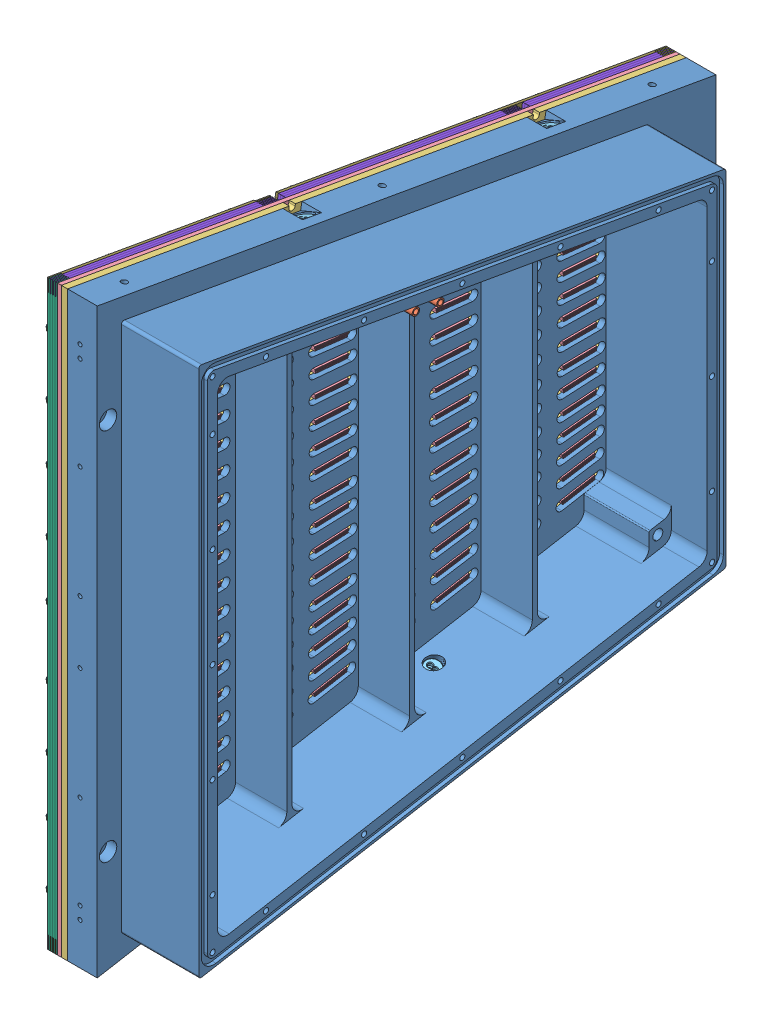
SolidWorks assembly KP_ALICE_TPC_UPGR_IROC_906100_A_0__IROC, configuration Default. Lengths in mm.
Overall size (107.25 467.04 496.5).
180 component instances, 16 part files, 0 mates.
Components (placement in the parent):
- KP_ALICE_TPC_UPGR_IROC_006100_P_0__IROC_alubody-1: KP_ALICE_TPC_UPGR_IROC_006100_P_0__IROC_alubody [Default] at origin size (85.8 467.04 496.5)
- KP_ALICE_TPC_UPGR_IROC_006200_P_0__IROC_cooling_pipe-1: KP_ALICE_TPC_UPGR_IROC_006200_P_0__IROC_cooling_pipe [Default] at origin size (87.18 411.15 421)
- KP_ALICE_TPC_UPGR_IROC_006110_P_0__IROC_strongback-1: KP_ALICE_TPC_UPGR_IROC_006110_P_0__IROC_strongback [Default] at origin size (5 467.04 496.5)
- KP_ALICE_TPC_UPGR_IROC_PADPL_006010_P_0__IROC_padplane-1: KP_ALICE_TPC_UPGR_IROC_PADPL_006010_P_0__IROC_padplane [Default] at (-5 0 0) size (12.25 467.04 496.5)
- KP_ALICE_TPC_UPGR_IROC_006105_P_0__Plug_Feedthrough-1: KP_ALICE_TPC_UPGR_IROC_006105_P_0__Plug_Feedthrough [Default] at (18.3176 -157.7833 228.3194) x (-0.93358 0.352924 0.06223) z (0 -0.173648 0.984808) size (14.4 25.16 13.6)
- KP_ALICE_TPC_UPGR_IROC_006105_P_0__Plug_Feedthrough-2: KP_ALICE_TPC_UPGR_IROC_006105_P_0__Plug_Feedthrough [Default] at (18.3176 -193.8152 432.667) x (-0.93358 0.352924 0.06223) z (0 -0.173648 0.984808) size (14.4 25.16 13.6)
- KP_ALICE_TPC_UPGR_IROC_006105_P_0__Plug_Feedthrough-3: KP_ALICE_TPC_UPGR_IROC_006105_P_0__Plug_Feedthrough [Default] at (18.3176 140.6789 131.3158) x (-0.93358 -0.352924 0.06223) z (0 -0.173648 -0.984808) size (14.4 25.16 13.6)
- KP_ALICE_TPC_UPGR_IROC_006105_P_0__Plug_Feedthrough-4: KP_ALICE_TPC_UPGR_IROC_006105_P_0__Plug_Feedthrough [Default] at (18.3176 175.2349 327.2925) x (-0.93358 -0.352924 0.06223) z (0 -0.173648 -0.984808) size (14.4 25.16 13.6)
- KP_ALICE_TPC_UPGR_GEM_GIF_906300_A_0__IROC-GEM-frame-1: KP_ALICE_TPC_UPGR_GEM_GIF_906300_A_0__IROC-GEM-frame [Default] at (-2.2 0 0) size (2 467.04 496.5)
  - KP_ALICE_TPC_UPGR_GEM_GIF_006310_P_0__IROC-GEM-frame-top-1: KP_ALICE_TPC_UPGR_GEM_GIF_006310_P_0__IROC-GEM-frame-top [Default] at (-6 0 0) size (2 467.04 10)
  - KP_ALICE_TPC_UPGR_GEM_GIF_006320_P_0__IROC-GEM-frame-bottom-1: KP_ALICE_TPC_UPGR_GEM_GIF_006320_P_0__IROC-GEM-frame-bottom [Default] at (-6 0 0) size (2 295.48 10)
  - KP_ALICE_TPC_UPGR_GEM_GIF_006330_P_0__IROC-GEM-frame-left-1: KP_ALICE_TPC_UPGR_GEM_GIF_006330_P_0__IROC-GEM-frame-left [Default] at (-6 0 0) size (2 97.7 496.5)
  - KP_ALICE_TPC_UPGR_GEM_GIF_006340_P_0__IROC-GEM-frame-right-1: KP_ALICE_TPC_UPGR_GEM_GIF_006340_P_0__IROC-GEM-frame-right [Default] at (-6 0 0) size (2 97.7 496.5)
  - KP_ALICE_TPC_UPGR_GEM_GIF_006351_P_0__IROC-GEM-frame-distance-strip_V-1: KP_ALICE_TPC_UPGR_GEM_GIF_006351_P_0__IROC-GEM-frame-distance-strip_V [Default] at (-6 0 0) size (2 1.5 481)
  - KP_ALICE_TPC_UPGR_GEM_GIF_006361_P_0__IROC-GEM-frame-distance-strip_H-1: KP_ALICE_TPC_UPGR_GEM_GIF_006361_P_0__IROC-GEM-frame-distance-strip_H [Default] at (-6 0 0) size (2 364.51 1.5)
- KP_ALICE_TPC_UPGR_GEM_GIF_906300_A_0__IROC-GEM-frame-2: KP_ALICE_TPC_UPGR_GEM_GIF_906300_A_0__IROC-GEM-frame [Default] at (-4.2 0 0) size (2 467.04 496.5)
  - KP_ALICE_TPC_UPGR_GEM_GIF_006310_P_0__IROC-GEM-frame-top-1: KP_ALICE_TPC_UPGR_GEM_GIF_006310_P_0__IROC-GEM-frame-top [Default] at (-6 0 0) size (2 467.04 10)
  - KP_ALICE_TPC_UPGR_GEM_GIF_006320_P_0__IROC-GEM-frame-bottom-1: KP_ALICE_TPC_UPGR_GEM_GIF_006320_P_0__IROC-GEM-frame-bottom [Default] at (-6 0 0) size (2 295.48 10)
  - KP_ALICE_TPC_UPGR_GEM_GIF_006330_P_0__IROC-GEM-frame-left-1: KP_ALICE_TPC_UPGR_GEM_GIF_006330_P_0__IROC-GEM-frame-left [Default] at (-6 0 0) size (2 97.7 496.5)
  - KP_ALICE_TPC_UPGR_GEM_GIF_006340_P_0__IROC-GEM-frame-right-1: KP_ALICE_TPC_UPGR_GEM_GIF_006340_P_0__IROC-GEM-frame-right [Default] at (-6 0 0) size (2 97.7 496.5)
  - KP_ALICE_TPC_UPGR_GEM_GIF_006351_P_0__IROC-GEM-frame-distance-strip_V-1: KP_ALICE_TPC_UPGR_GEM_GIF_006351_P_0__IROC-GEM-frame-distance-strip_V [Default] at (-6 0 0) size (2 1.5 481)
  - KP_ALICE_TPC_UPGR_GEM_GIF_006361_P_0__IROC-GEM-frame-distance-strip_H-1: KP_ALICE_TPC_UPGR_GEM_GIF_006361_P_0__IROC-GEM-frame-distance-strip_H [Default] at (-6 0 0) size (2 364.51 1.5)
- KP_ALICE_TPC_UPGR_GEM_GIF_906300_A_0__IROC-GEM-frame-3: KP_ALICE_TPC_UPGR_GEM_GIF_906300_A_0__IROC-GEM-frame [Default] at (-6.2 0 0) size (2 467.04 496.5)
  - KP_ALICE_TPC_UPGR_GEM_GIF_006310_P_0__IROC-GEM-frame-top-1: KP_ALICE_TPC_UPGR_GEM_GIF_006310_P_0__IROC-GEM-frame-top [Default] at (-6 0 0) size (2 467.04 10)
  - KP_ALICE_TPC_UPGR_GEM_GIF_006320_P_0__IROC-GEM-frame-bottom-1: KP_ALICE_TPC_UPGR_GEM_GIF_006320_P_0__IROC-GEM-frame-bottom [Default] at (-6 0 0) size (2 295.48 10)
  - KP_ALICE_TPC_UPGR_GEM_GIF_006330_P_0__IROC-GEM-frame-left-1: KP_ALICE_TPC_UPGR_GEM_GIF_006330_P_0__IROC-GEM-frame-left [Default] at (-6 0 0) size (2 97.7 496.5)
  - KP_ALICE_TPC_UPGR_GEM_GIF_006340_P_0__IROC-GEM-frame-right-1: KP_ALICE_TPC_UPGR_GEM_GIF_006340_P_0__IROC-GEM-frame-right [Default] at (-6 0 0) size (2 97.7 496.5)
  - KP_ALICE_TPC_UPGR_GEM_GIF_006351_P_0__IROC-GEM-frame-distance-strip_V-1: KP_ALICE_TPC_UPGR_GEM_GIF_006351_P_0__IROC-GEM-frame-distance-strip_V [Default] at (-6 0 0) size (2 1.5 481)
  - KP_ALICE_TPC_UPGR_GEM_GIF_006361_P_0__IROC-GEM-frame-distance-strip_H-1: KP_ALICE_TPC_UPGR_GEM_GIF_006361_P_0__IROC-GEM-frame-distance-strip_H [Default] at (-6 0 0) size (2 364.51 1.5)
- KP_ALICE_TPC_UPGR_GEM_GIF_906301_A_0__IROC-GEM1-frame-1: KP_ALICE_TPC_UPGR_GEM_GIF_906301_A_0__IROC-GEM1-frame [Default] at (-8.2 0 0) size (2 467.04 496.5)
  - KP_ALICE_TPC_UPGR_GEM_GIF_006310_P_0__IROC-GEM-frame-top-1: KP_ALICE_TPC_UPGR_GEM_GIF_006310_P_0__IROC-GEM-frame-top [Default] at (-6 0 0) size (2 467.04 10)
  - KP_ALICE_TPC_UPGR_GEM_GIF_006320_P_0__IROC-GEM-frame-bottom-1: KP_ALICE_TPC_UPGR_GEM_GIF_006320_P_0__IROC-GEM-frame-bottom [Default] at (-6 0 0) size (2 295.48 10)
  - KP_ALICE_TPC_UPGR_GEM_GIF_006331_P_0__IROC-GEM1-frame-left-1: KP_ALICE_TPC_UPGR_GEM_GIF_006331_P_0__IROC-GEM1-frame-left [Default] at (-6 0 0) size (2 97.7 496.5)
  - KP_ALICE_TPC_UPGR_GEM_GIF_006341_P_0__IROC-GEM1-frame-right-1: KP_ALICE_TPC_UPGR_GEM_GIF_006341_P_0__IROC-GEM1-frame-right [Default] at (-6 0 0) size (2 97.7 496.5)
  - KP_ALICE_TPC_UPGR_GEM_GIF_006351_P_0__IROC-GEM-frame-distance-strip_V-1: KP_ALICE_TPC_UPGR_GEM_GIF_006351_P_0__IROC-GEM-frame-distance-strip_V [Default] at (-6 0 0) size (2 1.5 481)
  - KP_ALICE_TPC_UPGR_GEM_GIF_006361_P_0__IROC-GEM-frame-distance-strip_H-1: KP_ALICE_TPC_UPGR_GEM_GIF_006361_P_0__IROC-GEM-frame-distance-strip_H [Default] at (-6 0 0) size (2 364.51 1.5)
- Mounting_bolt_GEM-frame-1: Mounting_bolt_GEM-frame [Default] at (-28.2 0 0) size (21 7 7)
  - KP_ALICE_TPC_UPGR_GEM_000111_P_0__GEM_mounting_bolt-1: KP_ALICE_TPC_UPGR_GEM_000111_P_0__GEM_mounting_bolt [Default] at (28.2 5 11.5) x (0 1 0) z (0 0 1) size (4 21 4)
  - Scheibe DIN 125 - 3,2-1: Scheibe DIN 125 - 3,2 [Default] at (12 5 11.5) x (0 0 1) z (-1 0 0) size (7 7 0.5)
  - Sechskantmutter ISO 4032 - M3-1: Sechskantmutter ISO 4032 - M3 [Default] at (11.5 5 11.5) x (0 0 1) z (-1 0 0) size (5.5 6.35 2.41)
- Mounting_bolt_GEM-frame-2: Mounting_bolt_GEM-frame [Default] at (-28.2 -55 0) size (21 7 7)
  - KP_ALICE_TPC_UPGR_GEM_000111_P_0__GEM_mounting_bolt-1: KP_ALICE_TPC_UPGR_GEM_000111_P_0__GEM_mounting_bolt [Default] at (28.2 5 11.5) x (0 1 0) z (0 0 1) size (4 21 4)
  - Scheibe DIN 125 - 3,2-1: Scheibe DIN 125 - 3,2 [Default] at (12 5 11.5) x (0 0 1) z (-1 0 0) size (7 7 0.5)
  - Sechskantmutter ISO 4032 - M3-1: Sechskantmutter ISO 4032 - M3 [Default] at (11.5 5 11.5) x (0 0 1) z (-1 0 0) size (5.5 6.35 2.41)
- Mounting_bolt_GEM-frame-3: Mounting_bolt_GEM-frame [Default] at (-28.2 -105 0) size (21 7 7)
  - KP_ALICE_TPC_UPGR_GEM_000111_P_0__GEM_mounting_bolt-1: KP_ALICE_TPC_UPGR_GEM_000111_P_0__GEM_mounting_bolt [Default] at (28.2 5 11.5) x (0 1 0) z (0 0 1) size (4 21 4)
  - Scheibe DIN 125 - 3,2-1: Scheibe DIN 125 - 3,2 [Default] at (12 5 11.5) x (0 0 1) z (-1 0 0) size (7 7 0.5)
  - Sechskantmutter ISO 4032 - M3-1: Sechskantmutter ISO 4032 - M3 [Default] at (11.5 5 11.5) x (0 0 1) z (-1 0 0) size (5.5 6.35 2.41)
- Mounting_bolt_GEM-frame-4: Mounting_bolt_GEM-frame [Default] at (-28.2 -146.1162 2) size (21 7 7)
  - KP_ALICE_TPC_UPGR_GEM_000111_P_0__GEM_mounting_bolt-1: KP_ALICE_TPC_UPGR_GEM_000111_P_0__GEM_mounting_bolt [Default] at (28.2 5 11.5) x (0 1 0) z (0 0 1) size (4 21 4)
  - Scheibe DIN 125 - 3,2-1: Scheibe DIN 125 - 3,2 [Default] at (12 5 11.5) x (0 0 1) z (-1 0 0) size (7 7 0.5)
  - Sechskantmutter ISO 4032 - M3-1: Sechskantmutter ISO 4032 - M3 [Default] at (11.5 5 11.5) x (0 0 1) z (-1 0 0) size (5.5 6.35 2.41)
- Mounting_bolt_GEM-frame-5: Mounting_bolt_GEM-frame [Default] at (-28.2 -189.6705 243.25) size (21 7 7)
  - KP_ALICE_TPC_UPGR_GEM_000111_P_0__GEM_mounting_bolt-1: KP_ALICE_TPC_UPGR_GEM_000111_P_0__GEM_mounting_bolt [Default] at (28.2 5 11.5) x (0 1 0) z (0 0 1) size (4 21 4)
  - Scheibe DIN 125 - 3,2-1: Scheibe DIN 125 - 3,2 [Default] at (12 5 11.5) x (0 0 1) z (-1 0 0) size (7 7 0.5)
  - Sechskantmutter ISO 4032 - M3-1: Sechskantmutter ISO 4032 - M3 [Default] at (11.5 5 11.5) x (0 0 1) z (-1 0 0) size (5.5 6.35 2.41)
- Mounting_bolt_GEM-frame-6: Mounting_bolt_GEM-frame [Default] at (-28.2 -198.3529 292.4904) size (21 7 7)
  - KP_ALICE_TPC_UPGR_GEM_000111_P_0__GEM_mounting_bolt-1: KP_ALICE_TPC_UPGR_GEM_000111_P_0__GEM_mounting_bolt [Default] at (28.2 5 11.5) x (0 1 0) z (0 0 1) size (4 21 4)
  - Scheibe DIN 125 - 3,2-1: Scheibe DIN 125 - 3,2 [Default] at (12 5 11.5) x (0 0 1) z (-1 0 0) size (7 7 0.5)
  - Sechskantmutter ISO 4032 - M3-1: Sechskantmutter ISO 4032 - M3 [Default] at (11.5 5 11.5) x (0 0 1) z (-1 0 0) size (5.5 6.35 2.41)
- Mounting_bolt_GEM-frame-7: Mounting_bolt_GEM-frame [Default] at (-28.2 -207.0354 341.7308) size (21 7 7)
  - KP_ALICE_TPC_UPGR_GEM_000111_P_0__GEM_mounting_bolt-1: KP_ALICE_TPC_UPGR_GEM_000111_P_0__GEM_mounting_bolt [Default] at (28.2 5 11.5) x (0 1 0) z (0 0 1) size (4 21 4)
  - Scheibe DIN 125 - 3,2-1: Scheibe DIN 125 - 3,2 [Default] at (12 5 11.5) x (0 0 1) z (-1 0 0) size (7 7 0.5)
  - Sechskantmutter ISO 4032 - M3-1: Sechskantmutter ISO 4032 - M3 [Default] at (11.5 5 11.5) x (0 0 1) z (-1 0 0) size (5.5 6.35 2.41)
- Mounting_bolt_GEM-frame-8: Mounting_bolt_GEM-frame [Default] at (-28.2 -215.7178 390.9712) size (21 7 7)
  - KP_ALICE_TPC_UPGR_GEM_000111_P_0__GEM_mounting_bolt-1: KP_ALICE_TPC_UPGR_GEM_000111_P_0__GEM_mounting_bolt [Default] at (28.2 5 11.5) x (0 1 0) z (0 0 1) size (4 21 4)
  - Scheibe DIN 125 - 3,2-1: Scheibe DIN 125 - 3,2 [Default] at (12 5 11.5) x (0 0 1) z (-1 0 0) size (7 7 0.5)
  - Sechskantmutter ISO 4032 - M3-1: Sechskantmutter ISO 4032 - M3 [Default] at (11.5 5 11.5) x (0 0 1) z (-1 0 0) size (5.5 6.35 2.41)
- Mounting_bolt_GEM-frame-9: Mounting_bolt_GEM-frame [Default] at (-28.2 -180.9881 194.0096) size (21 7 7)
  - KP_ALICE_TPC_UPGR_GEM_000111_P_0__GEM_mounting_bolt-1: KP_ALICE_TPC_UPGR_GEM_000111_P_0__GEM_mounting_bolt [Default] at (28.2 5 11.5) x (0 1 0) z (0 0 1) size (4 21 4)
  - Scheibe DIN 125 - 3,2-1: Scheibe DIN 125 - 3,2 [Default] at (12 5 11.5) x (0 0 1) z (-1 0 0) size (7 7 0.5)
  - Sechskantmutter ISO 4032 - M3-1: Sechskantmutter ISO 4032 - M3 [Default] at (11.5 5 11.5) x (0 0 1) z (-1 0 0) size (5.5 6.35 2.41)
- Mounting_bolt_GEM-frame-10: Mounting_bolt_GEM-frame [Default] at (-28.2 -172.3057 144.7692) size (21 7 7)
  - KP_ALICE_TPC_UPGR_GEM_000111_P_0__GEM_mounting_bolt-1: KP_ALICE_TPC_UPGR_GEM_000111_P_0__GEM_mounting_bolt [Default] at (28.2 5 11.5) x (0 1 0) z (0 0 1) size (4 21 4)
  - Scheibe DIN 125 - 3,2-1: Scheibe DIN 125 - 3,2 [Default] at (12 5 11.5) x (0 0 1) z (-1 0 0) size (7 7 0.5)
  - Sechskantmutter ISO 4032 - M3-1: Sechskantmutter ISO 4032 - M3 [Default] at (11.5 5 11.5) x (0 0 1) z (-1 0 0) size (5.5 6.35 2.41)
- Mounting_bolt_GEM-frame-11: Mounting_bolt_GEM-frame [Default] at (-28.2 -163.6233 95.5288) size (21 7 7)
  - KP_ALICE_TPC_UPGR_GEM_000111_P_0__GEM_mounting_bolt-1: KP_ALICE_TPC_UPGR_GEM_000111_P_0__GEM_mounting_bolt [Default] at (28.2 5 11.5) x (0 1 0) z (0 0 1) size (4 21 4)
  - Scheibe DIN 125 - 3,2-1: Scheibe DIN 125 - 3,2 [Default] at (12 5 11.5) x (0 0 1) z (-1 0 0) size (7 7 0.5)
  - Sechskantmutter ISO 4032 - M3-1: Sechskantmutter ISO 4032 - M3 [Default] at (11.5 5 11.5) x (0 0 1) z (-1 0 0) size (5.5 6.35 2.41)
- Mounting_bolt_GEM-frame-12: Mounting_bolt_GEM-frame [Default] at (-28.2 -231.194 484.5) size (21 7 7)
  - KP_ALICE_TPC_UPGR_GEM_000111_P_0__GEM_mounting_bolt-1: KP_ALICE_TPC_UPGR_GEM_000111_P_0__GEM_mounting_bolt [Default] at (28.2 5 11.5) x (0 1 0) z (0 0 1) size (4 21 4)
  - Scheibe DIN 125 - 3,2-1: Scheibe DIN 125 - 3,2 [Default] at (12 5 11.5) x (0 0 1) z (-1 0 0) size (7 7 0.5)
  - Sechskantmutter ISO 4032 - M3-1: Sechskantmutter ISO 4032 - M3 [Default] at (11.5 5 11.5) x (0 0 1) z (-1 0 0) size (5.5 6.35 2.41)
- Mounting_bolt_GEM-frame-13: Mounting_bolt_GEM-frame [Default] at (-28.2 0 486.5) size (21 7 7)
  - KP_ALICE_TPC_UPGR_GEM_000111_P_0__GEM_mounting_bolt-1: KP_ALICE_TPC_UPGR_GEM_000111_P_0__GEM_mounting_bolt [Default] at (28.2 5 11.5) x (0 1 0) z (0 0 1) size (4 21 4)
  - Scheibe DIN 125 - 3,2-1: Scheibe DIN 125 - 3,2 [Default] at (12 5 11.5) x (0 0 1) z (-1 0 0) size (7 7 0.5)
  - Sechskantmutter ISO 4032 - M3-1: Sechskantmutter ISO 4032 - M3 [Default] at (11.5 5 11.5) x (0 0 1) z (-1 0 0) size (5.5 6.35 2.41)
- Mounting_bolt_GEM-frame-14: Mounting_bolt_GEM-frame [Default] at (-28.2 -55 486.5) size (21 7 7)
  - KP_ALICE_TPC_UPGR_GEM_000111_P_0__GEM_mounting_bolt-1: KP_ALICE_TPC_UPGR_GEM_000111_P_0__GEM_mounting_bolt [Default] at (28.2 5 11.5) x (0 1 0) z (0 0 1) size (4 21 4)
  - Scheibe DIN 125 - 3,2-1: Scheibe DIN 125 - 3,2 [Default] at (12 5 11.5) x (0 0 1) z (-1 0 0) size (7 7 0.5)
  - Sechskantmutter ISO 4032 - M3-1: Sechskantmutter ISO 4032 - M3 [Default] at (11.5 5 11.5) x (0 0 1) z (-1 0 0) size (5.5 6.35 2.41)
- Mounting_bolt_GEM-frame-15: Mounting_bolt_GEM-frame [Default] at (-28.2 -105 486.5) size (21 7 7)
  - KP_ALICE_TPC_UPGR_GEM_000111_P_0__GEM_mounting_bolt-1: KP_ALICE_TPC_UPGR_GEM_000111_P_0__GEM_mounting_bolt [Default] at (28.2 5 11.5) x (0 1 0) z (0 0 1) size (4 21 4)
  - Scheibe DIN 125 - 3,2-1: Scheibe DIN 125 - 3,2 [Default] at (12 5 11.5) x (0 0 1) z (-1 0 0) size (7 7 0.5)
  - Sechskantmutter ISO 4032 - M3-1: Sechskantmutter ISO 4032 - M3 [Default] at (11.5 5 11.5) x (0 0 1) z (-1 0 0) size (5.5 6.35 2.41)
- Mounting_bolt_GEM-frame-16: Mounting_bolt_GEM-frame [Default] at (-28.2 -150 486.5) size (21 7 7)
  - KP_ALICE_TPC_UPGR_GEM_000111_P_0__GEM_mounting_bolt-1: KP_ALICE_TPC_UPGR_GEM_000111_P_0__GEM_mounting_bolt [Default] at (28.2 5 11.5) x (0 1 0) z (0 0 1) size (4 21 4)
  - Scheibe DIN 125 - 3,2-1: Scheibe DIN 125 - 3,2 [Default] at (12 5 11.5) x (0 0 1) z (-1 0 0) size (7 7 0.5)
  - Sechskantmutter ISO 4032 - M3-1: Sechskantmutter ISO 4032 - M3 [Default] at (11.5 5 11.5) x (0 0 1) z (-1 0 0) size (5.5 6.35 2.41)
- Mounting_bolt_GEM-frame-17: Mounting_bolt_GEM-frame [Default] at (-28.2 -200 486.5) size (21 7 7)
  - KP_ALICE_TPC_UPGR_GEM_000111_P_0__GEM_mounting_bolt-1: KP_ALICE_TPC_UPGR_GEM_000111_P_0__GEM_mounting_bolt [Default] at (28.2 5 11.5) x (0 1 0) z (0 0 1) size (4 21 4)
  - Scheibe DIN 125 - 3,2-1: Scheibe DIN 125 - 3,2 [Default] at (12 5 11.5) x (0 0 1) z (-1 0 0) size (7 7 0.5)
  - Sechskantmutter ISO 4032 - M3-1: Sechskantmutter ISO 4032 - M3 [Default] at (11.5 5 11.5) x (0 0 1) z (-1 0 0) size (5.5 6.35 2.41)
- Mounting_bolt_GEM-frame-18: Mounting_bolt_GEM-frame [Default] at (-28.2 45 0) size (21 7 7)
  - KP_ALICE_TPC_UPGR_GEM_000111_P_0__GEM_mounting_bolt-1: KP_ALICE_TPC_UPGR_GEM_000111_P_0__GEM_mounting_bolt [Default] at (28.2 5 11.5) x (0 1 0) z (0 0 1) size (4 21 4)
  - Scheibe DIN 125 - 3,2-1: Scheibe DIN 125 - 3,2 [Default] at (12 5 11.5) x (0 0 1) z (-1 0 0) size (7 7 0.5)
  - Sechskantmutter ISO 4032 - M3-1: Sechskantmutter ISO 4032 - M3 [Default] at (11.5 5 11.5) x (0 0 1) z (-1 0 0) size (5.5 6.35 2.41)
- Mounting_bolt_GEM-frame-19: Mounting_bolt_GEM-frame [Default] at (-28.2 95 0) size (21 7 7)
  - KP_ALICE_TPC_UPGR_GEM_000111_P_0__GEM_mounting_bolt-1: KP_ALICE_TPC_UPGR_GEM_000111_P_0__GEM_mounting_bolt [Default] at (28.2 5 11.5) x (0 1 0) z (0 0 1) size (4 21 4)
  - Scheibe DIN 125 - 3,2-1: Scheibe DIN 125 - 3,2 [Default] at (12 5 11.5) x (0 0 1) z (-1 0 0) size (7 7 0.5)
  - Sechskantmutter ISO 4032 - M3-1: Sechskantmutter ISO 4032 - M3 [Default] at (11.5 5 11.5) x (0 0 1) z (-1 0 0) size (5.5 6.35 2.41)
- Mounting_bolt_GEM-frame-20: Mounting_bolt_GEM-frame [Default] at (-28.2 136.1162 2) size (21 7 7)
  - KP_ALICE_TPC_UPGR_GEM_000111_P_0__GEM_mounting_bolt-1: KP_ALICE_TPC_UPGR_GEM_000111_P_0__GEM_mounting_bolt [Default] at (28.2 5 11.5) x (0 1 0) z (0 0 1) size (4 21 4)
  - Scheibe DIN 125 - 3,2-1: Scheibe DIN 125 - 3,2 [Default] at (12 5 11.5) x (0 0 1) z (-1 0 0) size (7 7 0.5)
  - Sechskantmutter ISO 4032 - M3-1: Sechskantmutter ISO 4032 - M3 [Default] at (11.5 5 11.5) x (0 0 1) z (-1 0 0) size (5.5 6.35 2.41)
- Mounting_bolt_GEM-frame-21: Mounting_bolt_GEM-frame [Default] at (-28.2 179.6705 243.25) size (21 7 7)
  - KP_ALICE_TPC_UPGR_GEM_000111_P_0__GEM_mounting_bolt-1: KP_ALICE_TPC_UPGR_GEM_000111_P_0__GEM_mounting_bolt [Default] at (28.2 5 11.5) x (0 1 0) z (0 0 1) size (4 21 4)
  - Scheibe DIN 125 - 3,2-1: Scheibe DIN 125 - 3,2 [Default] at (12 5 11.5) x (0 0 1) z (-1 0 0) size (7 7 0.5)
  - Sechskantmutter ISO 4032 - M3-1: Sechskantmutter ISO 4032 - M3 [Default] at (11.5 5 11.5) x (0 0 1) z (-1 0 0) size (5.5 6.35 2.41)
- Mounting_bolt_GEM-frame-22: Mounting_bolt_GEM-frame [Default] at (-28.2 188.3529 292.4904) size (21 7 7)
  - KP_ALICE_TPC_UPGR_GEM_000111_P_0__GEM_mounting_bolt-1: KP_ALICE_TPC_UPGR_GEM_000111_P_0__GEM_mounting_bolt [Default] at (28.2 5 11.5) x (0 1 0) z (0 0 1) size (4 21 4)
  - Scheibe DIN 125 - 3,2-1: Scheibe DIN 125 - 3,2 [Default] at (12 5 11.5) x (0 0 1) z (-1 0 0) size (7 7 0.5)
  - Sechskantmutter ISO 4032 - M3-1: Sechskantmutter ISO 4032 - M3 [Default] at (11.5 5 11.5) x (0 0 1) z (-1 0 0) size (5.5 6.35 2.41)
- Mounting_bolt_GEM-frame-23: Mounting_bolt_GEM-frame [Default] at (-28.2 197.0354 341.7308) size (21 7 7)
  - KP_ALICE_TPC_UPGR_GEM_000111_P_0__GEM_mounting_bolt-1: KP_ALICE_TPC_UPGR_GEM_000111_P_0__GEM_mounting_bolt [Default] at (28.2 5 11.5) x (0 1 0) z (0 0 1) size (4 21 4)
  - Scheibe DIN 125 - 3,2-1: Scheibe DIN 125 - 3,2 [Default] at (12 5 11.5) x (0 0 1) z (-1 0 0) size (7 7 0.5)
  - Sechskantmutter ISO 4032 - M3-1: Sechskantmutter ISO 4032 - M3 [Default] at (11.5 5 11.5) x (0 0 1) z (-1 0 0) size (5.5 6.35 2.41)
- Mounting_bolt_GEM-frame-24: Mounting_bolt_GEM-frame [Default] at (-28.2 205.7178 390.9712) size (21 7 7)
  - KP_ALICE_TPC_UPGR_GEM_000111_P_0__GEM_mounting_bolt-1: KP_ALICE_TPC_UPGR_GEM_000111_P_0__GEM_mounting_bolt [Default] at (28.2 5 11.5) x (0 1 0) z (0 0 1) size (4 21 4)
  - Scheibe DIN 125 - 3,2-1: Scheibe DIN 125 - 3,2 [Default] at (12 5 11.5) x (0 0 1) z (-1 0 0) size (7 7 0.5)
  - Sechskantmutter ISO 4032 - M3-1: Sechskantmutter ISO 4032 - M3 [Default] at (11.5 5 11.5) x (0 0 1) z (-1 0 0) size (5.5 6.35 2.41)
- Mounting_bolt_GEM-frame-25: Mounting_bolt_GEM-frame [Default] at (-28.2 170.9881 194.0096) size (21 7 7)
  - KP_ALICE_TPC_UPGR_GEM_000111_P_0__GEM_mounting_bolt-1: KP_ALICE_TPC_UPGR_GEM_000111_P_0__GEM_mounting_bolt [Default] at (28.2 5 11.5) x (0 1 0) z (0 0 1) size (4 21 4)
  - Scheibe DIN 125 - 3,2-1: Scheibe DIN 125 - 3,2 [Default] at (12 5 11.5) x (0 0 1) z (-1 0 0) size (7 7 0.5)
  - Sechskantmutter ISO 4032 - M3-1: Sechskantmutter ISO 4032 - M3 [Default] at (11.5 5 11.5) x (0 0 1) z (-1 0 0) size (5.5 6.35 2.41)
- Mounting_bolt_GEM-frame-26: Mounting_bolt_GEM-frame [Default] at (-28.2 162.3057 144.7692) size (21 7 7)
  - KP_ALICE_TPC_UPGR_GEM_000111_P_0__GEM_mounting_bolt-1: KP_ALICE_TPC_UPGR_GEM_000111_P_0__GEM_mounting_bolt [Default] at (28.2 5 11.5) x (0 1 0) z (0 0 1) size (4 21 4)
  - Scheibe DIN 125 - 3,2-1: Scheibe DIN 125 - 3,2 [Default] at (12 5 11.5) x (0 0 1) z (-1 0 0) size (7 7 0.5)
  - Sechskantmutter ISO 4032 - M3-1: Sechskantmutter ISO 4032 - M3 [Default] at (11.5 5 11.5) x (0 0 1) z (-1 0 0) size (5.5 6.35 2.41)
- Mounting_bolt_GEM-frame-27: Mounting_bolt_GEM-frame [Default] at (-28.2 153.6233 95.5288) size (21 7 7)
  - KP_ALICE_TPC_UPGR_GEM_000111_P_0__GEM_mounting_bolt-1: KP_ALICE_TPC_UPGR_GEM_000111_P_0__GEM_mounting_bolt [Default] at (28.2 5 11.5) x (0 1 0) z (0 0 1) size (4 21 4)
  - Scheibe DIN 125 - 3,2-1: Scheibe DIN 125 - 3,2 [Default] at (12 5 11.5) x (0 0 1) z (-1 0 0) size (7 7 0.5)
  - Sechskantmutter ISO 4032 - M3-1: Sechskantmutter ISO 4032 - M3 [Default] at (11.5 5 11.5) x (0 0 1) z (-1 0 0) size (5.5 6.35 2.41)
- Mounting_bolt_GEM-frame-28: Mounting_bolt_GEM-frame [Default] at (-28.2 221.194 484.5) size (21 7 7)
  - KP_ALICE_TPC_UPGR_GEM_000111_P_0__GEM_mounting_bolt-1: KP_ALICE_TPC_UPGR_GEM_000111_P_0__GEM_mounting_bolt [Default] at (28.2 5 11.5) x (0 1 0) z (0 0 1) size (4 21 4)
  - Scheibe DIN 125 - 3,2-1: Scheibe DIN 125 - 3,2 [Default] at (12 5 11.5) x (0 0 1) z (-1 0 0) size (7 7 0.5)
  - Sechskantmutter ISO 4032 - M3-1: Sechskantmutter ISO 4032 - M3 [Default] at (11.5 5 11.5) x (0 0 1) z (-1 0 0) size (5.5 6.35 2.41)
- Mounting_bolt_GEM-frame-29: Mounting_bolt_GEM-frame [Default] at (-28.2 45 486.5) size (21 7 7)
  - KP_ALICE_TPC_UPGR_GEM_000111_P_0__GEM_mounting_bolt-1: KP_ALICE_TPC_UPGR_GEM_000111_P_0__GEM_mounting_bolt [Default] at (28.2 5 11.5) x (0 1 0) z (0 0 1) size (4 21 4)
  - Scheibe DIN 125 - 3,2-1: Scheibe DIN 125 - 3,2 [Default] at (12 5 11.5) x (0 0 1) z (-1 0 0) size (7 7 0.5)
  - Sechskantmutter ISO 4032 - M3-1: Sechskantmutter ISO 4032 - M3 [Default] at (11.5 5 11.5) x (0 0 1) z (-1 0 0) size (5.5 6.35 2.41)
- Mounting_bolt_GEM-frame-30: Mounting_bolt_GEM-frame [Default] at (-28.2 95 486.5) size (21 7 7)
  - KP_ALICE_TPC_UPGR_GEM_000111_P_0__GEM_mounting_bolt-1: KP_ALICE_TPC_UPGR_GEM_000111_P_0__GEM_mounting_bolt [Default] at (28.2 5 11.5) x (0 1 0) z (0 0 1) size (4 21 4)
  - Scheibe DIN 125 - 3,2-1: Scheibe DIN 125 - 3,2 [Default] at (12 5 11.5) x (0 0 1) z (-1 0 0) size (7 7 0.5)
  - Sechskantmutter ISO 4032 - M3-1: Sechskantmutter ISO 4032 - M3 [Default] at (11.5 5 11.5) x (0 0 1) z (-1 0 0) size (5.5 6.35 2.41)
- Mounting_bolt_GEM-frame-31: Mounting_bolt_GEM-frame [Default] at (-28.2 140 486.5) size (21 7 7)
  - KP_ALICE_TPC_UPGR_GEM_000111_P_0__GEM_mounting_bolt-1: KP_ALICE_TPC_UPGR_GEM_000111_P_0__GEM_mounting_bolt [Default] at (28.2 5 11.5) x (0 1 0) z (0 0 1) size (4 21 4)
  - Scheibe DIN 125 - 3,2-1: Scheibe DIN 125 - 3,2 [Default] at (12 5 11.5) x (0 0 1) z (-1 0 0) size (7 7 0.5)
  - Sechskantmutter ISO 4032 - M3-1: Sechskantmutter ISO 4032 - M3 [Default] at (11.5 5 11.5) x (0 0 1) z (-1 0 0) size (5.5 6.35 2.41)
- Mounting_bolt_GEM-frame-32: Mounting_bolt_GEM-frame [Default] at (-28.2 190 486.5) size (21 7 7)
  - KP_ALICE_TPC_UPGR_GEM_000111_P_0__GEM_mounting_bolt-1: KP_ALICE_TPC_UPGR_GEM_000111_P_0__GEM_mounting_bolt [Default] at (28.2 5 11.5) x (0 1 0) z (0 0 1) size (4 21 4)
  - Scheibe DIN 125 - 3,2-1: Scheibe DIN 125 - 3,2 [Default] at (12 5 11.5) x (0 0 1) z (-1 0 0) size (7 7 0.5)
  - Sechskantmutter ISO 4032 - M3-1: Sechskantmutter ISO 4032 - M3 [Default] at (11.5 5 11.5) x (0 0 1) z (-1 0 0) size (5.5 6.35 2.41)
- Mounting_bolt_GEM-frame-33: Mounting_bolt_GEM-frame [Default] at (-28.2 -154.9409 46.2884) size (21 7 7)
  - KP_ALICE_TPC_UPGR_GEM_000111_P_0__GEM_mounting_bolt-1: KP_ALICE_TPC_UPGR_GEM_000111_P_0__GEM_mounting_bolt [Default] at (28.2 5 11.5) x (0 1 0) z (0 0 1) size (4 21 4)
  - Scheibe DIN 125 - 3,2-1: Scheibe DIN 125 - 3,2 [Default] at (12 5 11.5) x (0 0 1) z (-1 0 0) size (7 7 0.5)
  - Sechskantmutter ISO 4032 - M3-1: Sechskantmutter ISO 4032 - M3 [Default] at (11.5 5 11.5) x (0 0 1) z (-1 0 0) size (5.5 6.35 2.41)
- Mounting_bolt_GEM-frame-34: Mounting_bolt_GEM-frame [Default] at (-28.2 -224.4002 440.2116) size (21 7 7)
  - KP_ALICE_TPC_UPGR_GEM_000111_P_0__GEM_mounting_bolt-1: KP_ALICE_TPC_UPGR_GEM_000111_P_0__GEM_mounting_bolt [Default] at (28.2 5 11.5) x (0 1 0) z (0 0 1) size (4 21 4)
  - Scheibe DIN 125 - 3,2-1: Scheibe DIN 125 - 3,2 [Default] at (12 5 11.5) x (0 0 1) z (-1 0 0) size (7 7 0.5)
  - Sechskantmutter ISO 4032 - M3-1: Sechskantmutter ISO 4032 - M3 [Default] at (11.5 5 11.5) x (0 0 1) z (-1 0 0) size (5.5 6.35 2.41)
- Mounting_bolt_GEM-frame-35: Mounting_bolt_GEM-frame [Default] at (-28.2 214.4002 440.2116) size (21 7 7)
  - KP_ALICE_TPC_UPGR_GEM_000111_P_0__GEM_mounting_bolt-1: KP_ALICE_TPC_UPGR_GEM_000111_P_0__GEM_mounting_bolt [Default] at (28.2 5 11.5) x (0 1 0) z (0 0 1) size (4 21 4)
  - Scheibe DIN 125 - 3,2-1: Scheibe DIN 125 - 3,2 [Default] at (12 5 11.5) x (0 0 1) z (-1 0 0) size (7 7 0.5)
  - Sechskantmutter ISO 4032 - M3-1: Sechskantmutter ISO 4032 - M3 [Default] at (11.5 5 11.5) x (0 0 1) z (-1 0 0) size (5.5 6.35 2.41)
- Mounting_bolt_GEM-frame-36: Mounting_bolt_GEM-frame [Default] at (-28.2 144.9409 46.2884) size (21 7 7)
  - KP_ALICE_TPC_UPGR_GEM_000111_P_0__GEM_mounting_bolt-1: KP_ALICE_TPC_UPGR_GEM_000111_P_0__GEM_mounting_bolt [Default] at (28.2 5 11.5) x (0 1 0) z (0 0 1) size (4 21 4)
  - Scheibe DIN 125 - 3,2-1: Scheibe DIN 125 - 3,2 [Default] at (12 5 11.5) x (0 0 1) z (-1 0 0) size (7 7 0.5)
  - Sechskantmutter ISO 4032 - M3-1: Sechskantmutter ISO 4032 - M3 [Default] at (11.5 5 11.5) x (0 0 1) z (-1 0 0) size (5.5 6.35 2.41)
